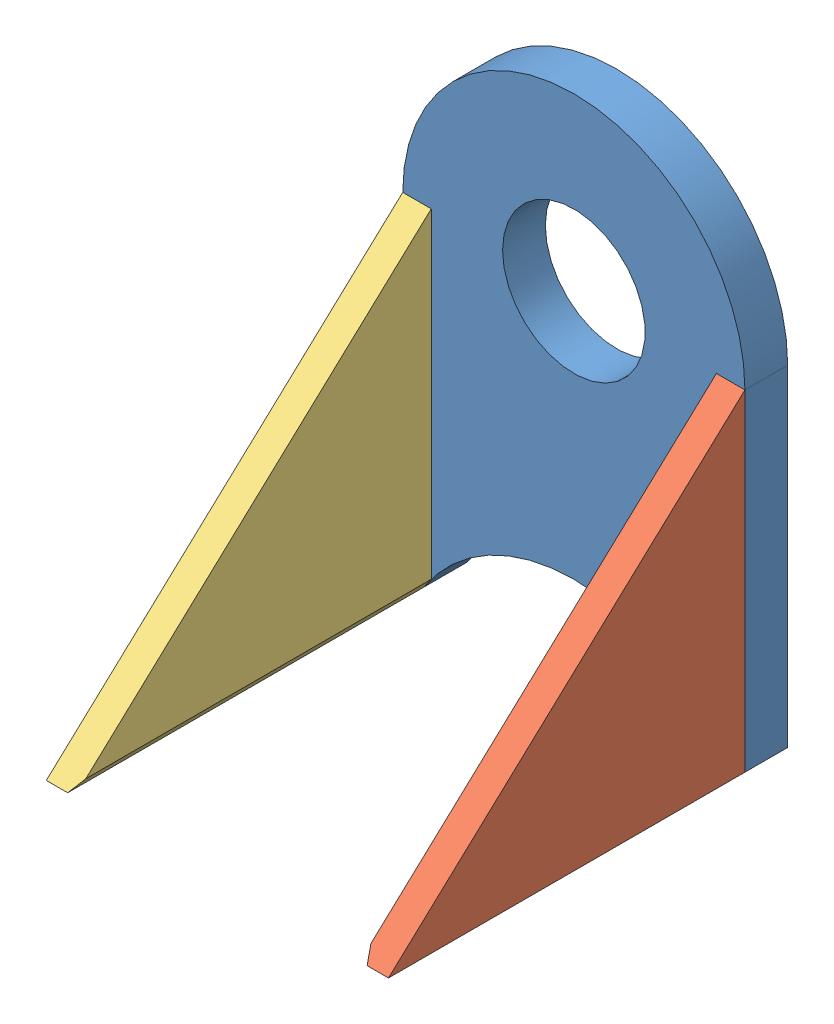
SolidWorks assembly PUTM-S-TR-GR-Motor-Attachment-Assembly 1, configuration Domyślna. Lengths in mm.
Overall size (24 35.22 28).
3 component instances, 3 part files, 6 mates.
Components (placement in the parent):
- PUTM-S-TR-GR-Motor-Attachment-1-1: PUTM-S-TR-GR-Motor-Attachment-1 [Domyślna] at (-23.9758 4.5454 35.2177) size (24 35.22 3)
- PUTM-S-TR-GR-Motor-Attachment-2-1: PUTM-S-TR-GR-Motor-Attachment-2 [Domyślna] at (-13.4758 -18.6723 36.7177) x (0 -1 0) z (-1 0 0) size (23.22 25 2)
- PUTM-S-TR-GR-Motor-Attachment-3-1: PUTM-S-TR-GR-Motor-Attachment-3 [Domyślna] at (-35.4758 -18.6723 36.7177) x (0 -1 0) z (-1 0 0) size (23.22 25 2)
Mates (geometry in assembly coordinates):
- Wspólnie2: coincident aligned: plane of PUTM-H-DT-Motor-Attachment-1-1 through (-11.9758 4.5454 36.7177) normal (1 0 0); plane of PUTM-H-DT-Motor-Attachment-2-1 through (-11.9758 -18.6723 36.7177) normal (1 0 0)
- Wspólnie3: coincident aligned: plane of PUTM-H-DT-Motor-Attachment-1-1 through (-11.9758 -18.6723 36.7177) normal (0 -1 0); plane of PUTM-H-DT-Motor-Attachment-2-1 through (-13.9758 -18.6723 61.7177) normal (0 -1 0)
- Wspólnie4: coincident anti-aligned: plane of PUTM-H-DT-Motor-Attachment-1-1 through (-23.9758 4.5454 36.7177) normal (0 0 1); plane of PUTM-H-DT-Motor-Attachment-2-1 through (-13.9758 -18.6723 36.7177) normal (0 0 -1)
- Wspólnie5: coincident aligned: plane of PUTM-H-DT-Motor-Attachment-1-1 through (-35.9758 -18.6723 36.7177) normal (-1 0 0); plane of PUTM-H-DT-Motor-Attachment-3-1 through (-35.9758 -18.6723 36.7177) normal (-1 0 0)
- Wspólnie6: coincident anti-aligned: plane of PUTM-H-DT-Motor-Attachment-1-1 through (-23.9758 4.5454 36.7177) normal (0 0 1); plane of PUTM-H-DT-Motor-Attachment-3-1 through (-35.9758 -18.6723 36.7177) normal (0 0 -1)
- Wspólnie7: coincident aligned: plane of PUTM-H-DT-Motor-Attachment-1-1 through (-34.4758 -18.6723 36.7177) normal (0 -1 0); plane of PUTM-H-DT-Motor-Attachment-3-1 through (-35.9758 -18.6723 61.7177) normal (0 -1 0)
